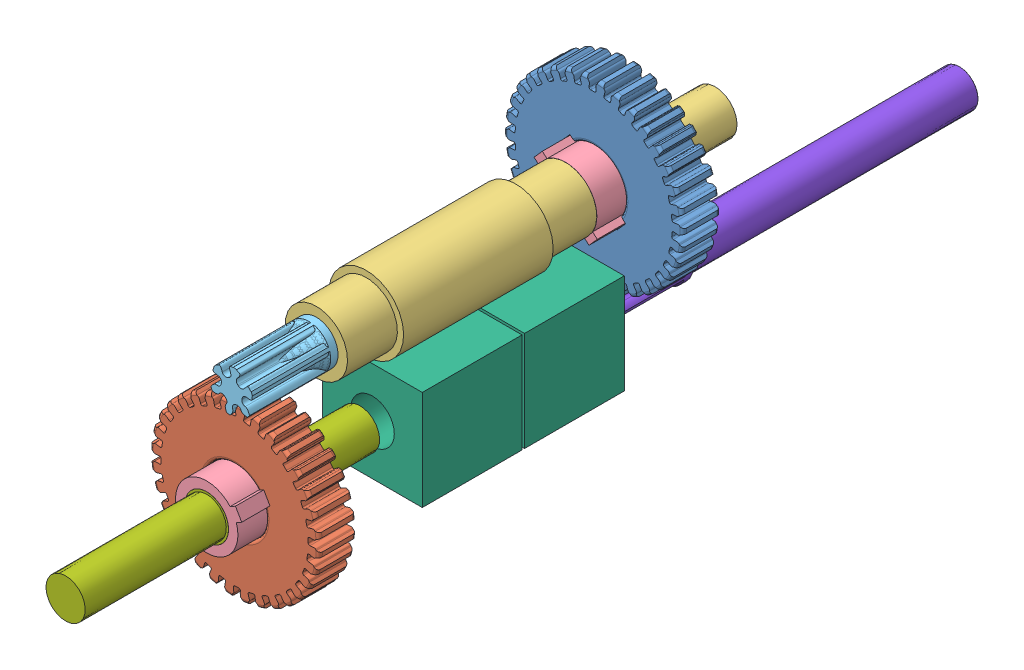
SolidWorks assembly Gear, configuration Default. Lengths in mm.
Overall size (64.62 86.42 227.72).
12 component instances, 10 part files, 29 mates.
Components (placement in the parent):
- drill-1: drill [Default] at (-20.9902 -5.8686 -75.9138) size (76.2 76.2 76.2) (hidden)
- 34 Tooth Gear-1: 34 Tooth Gear [Default] at (-20.9902 46.4985 -21.6848) x (0 0 -1) z (-0.664493 -0.747295 0) size (9.5 45.81 45.73)
- 32 Tooth Gear-1: 32 Tooth Gear [Default] at (-20.9902 21.924 60.3572) x (0 0 1) z (0.497661 -0.867372 0) size (9.51 43.27 43.27)
- shaft-1: shaft [Default] at (-20.9902 46.4985 -9.8738) x (0.670826 0.741614 0) z (0 0 1) size (19.05 19.05 101.6)
- Bushing GAB20A-1: Bushing GAB20A [Default] at (-20.9902 46.4985 -28.9238) x (0 0 1) z (0.664493 0.747295 0) size (19.05 18.72 15.88)
- Bushing GAB20A-2: Bushing GAB20A [Default] at (-20.9902 21.924 62.5162) x (0 0 1) z (-0.497661 0.867372 0) size (19.05 18.72 15.88)
- 6 Tooth Pinion 1-2: 6 Tooth Pinion 1 [Default] at (-20.9902 46.4985 74.2002) x (0 0 -1) z (-0.987719 0.15624 0) size (59.69 11.6 11.05)
- otherside-1: otherside [Default] at (-20.9902 9.224 0.5962) x (-1 0 0) z (0 0 -1) size (25.4 25.4 25.4)
- Shaft2-1: Shaft2 [Default] at (-20.9902 21.924 42.5162) x (-0.998091 -0.061753 0) z (0 0 1) size (11.13 11.13 75)
- case-1: case [Default] at (-20.9902 32.2314 -37.8138) x (-1 0 0) z (0 0 -1) size (50.8 76.2 127) (hidden)
- 6 Tooth Pinion 2-1: 6 Tooth Pinion 2 [Default] at (-20.9902 20.654 -16.2746) x (0 0 -1) z (-0.304987 -0.952356 0) size (94.95 11.6 11.05)
- otherside-2: otherside [Default] at (-20.9902 9.224 26.645) x (-1 0 0) z (0 0 -1) size (25.4 25.4 25.4)
Mates (geometry in assembly coordinates):
- Concentric3: concentric anti-aligned: cylinder of shaft-1 through (-20.9902 46.4985 -47.9738) axis (0 0 1) radius 5.5626; cylinder of Bushing GAB20A-1 through (-20.9902 46.4985 5.8596) axis (0 0 -1) radius 5.5626
- Concentric4: concentric anti-aligned: circle of 34 Tooth Gear-1; circle of Bushing GAB20A-1
- Parallel2: parallel anti-aligned: line of 34 Tooth Gear-1 through (-14.964 38.9987 -16.9858) axis (0.664493 0.747295 0); line of Bushing GAB20A-1 through (-12.9407 41.4652 -9.8738) axis (-0.664493 -0.747295 0)
- Concentric5: concentric anti-aligned: circle of drill-1; circle of shaft-1
- Distance4: distance = 2.54 mm aligned: plane of Bushing GAB20A-1 through (-20.9902 46.4985 -28.9238) normal (0 0 -1); plane of 34 Tooth Gear-1 through (-4.1765 35.2417 -26.3838) normal (0 0 -1)
- Parallel3: parallel aligned: plane of drill-1 through (-59.0902 70.3314 -37.8138) normal (-1 0 0); plane of otherside-1 through (-33.6902 34.624 -12.1038) normal (-1 0 0)
- Concentric6: concentric anti-aligned: circle of otherside-1; circle of Shaft2-1
- Concentric7: concentric anti-aligned: circle of Bushing GAB20A-2; circle of Shaft2-1
- Concentric8: concentric anti-aligned: circle of 32 Tooth Gear-1; circle of Bushing GAB20A-2
- Distance6: distance = 8.89 mm anti-aligned: plane of shaft-1 through (-20.9902 46.4985 53.6262) normal (0 0 1); plane of Bushing GAB20A-2 through (-20.9902 21.924 62.5162) normal (0 0 -1)
- Distance7: distance = 2.54 mm aligned: plane of 32 Tooth Gear-1 through (-35.889 10.1878 65.0562) normal (0 0 -1); plane of Bushing GAB20A-2 through (-20.9902 21.924 62.5162) normal (0 0 -1)
- Parallel4: parallel anti-aligned: line of 32 Tooth Gear-1 through (-11.9652 25.2573 65.0562) axis (-0.497661 0.867372 0); line of Bushing GAB20A-2 through (-13.6617 27.959 62.5162) axis (0.497661 -0.867372 0)
- GearMate2: gear = 152.4 : 812.8 mm: circle of 32 Tooth Gear-1; circle of 6 Tooth Pinion 1-2
- Concentric14: concentric aligned: circle of drill-1; circle of otherside-1
- Distance8: distance = 27.94 mm anti-aligned: plane of drill-1 through (-59.0902 70.3314 -37.8138) normal (0 0 1); plane of shaft-1 through (-20.9902 46.4985 -9.8738) normal (0 0 -1)
- Coincident20: coincident anti-aligned: plane of drill-1 through (-59.0902 70.3314 -37.8138) normal (0 0 1); plane of case-1 through (-46.3902 70.3314 -37.8138) normal (0 0 -1)
- Parallel6: parallel aligned: line of drill-1 through (17.1098 70.3314 -114.0138) axis (-1 0 0); line of case-1 through (4.4098 70.3314 -37.8138) axis (-1 0 0)
- Coincident21: coincident anti-aligned: line of drill-1 through (-59.0902 70.3314 -37.8138) axis (1 0 0); line of case-1 through (4.4098 70.3314 -37.8138) axis (-1 0 0)
- Concentric18: concentric aligned: circle of otherside-1; circle of case-1
- Distance9: distance = 0 mm anti-aligned: plane of Bushing GAB20A-1 through (-20.9902 46.4985 -9.8738) normal (0 0 1); plane of shaft-1 through (-20.9902 46.4985 -9.8738) normal (0 0 -1)
- Concentric21: concentric aligned: circle of drill-1; circle of 6 Tooth Pinion 2-1
- Coincident27: coincident anti-aligned: plane of drill-1 through (-20.9902 20.654 -110.2038) normal (0 0 1); plane of 6 Tooth Pinion 2-1 through (-20.9902 20.654 -110.2038) normal (0 0 -1)
- GearMate5: gear = 152.4 : 863.6 mm: circle of 34 Tooth Gear-1; circle of 6 Tooth Pinion 2-1
- Coincident28: coincident anti-aligned: plane of shaft-1 through (-20.9902 46.4985 53.6262) normal (0 0 1); plane of 6 Tooth Pinion 1-2 through (-20.9902 46.4985 53.6262) normal (0 0 -1)
- Concentric23: concentric anti-aligned: circle of shaft-1; circle of 6 Tooth Pinion 1-2
- Parallel7: parallel aligned: plane of otherside-1 through (-8.2902 34.624 -12.1038) normal (1 0 0); plane of otherside-2 through (-8.2902 34.624 13.945) normal (1 0 0)
- Parallel8: parallel aligned: plane of otherside-1 through (-20.9902 34.624 0.5962) normal (0 1 0); plane of otherside-2 through (-20.9902 34.624 26.645) normal (0 1 0)
- Coincident29: coincident aligned: line of otherside-1 through (-8.2902 34.624 -12.1038) axis (0 0 1); line of otherside-2 through (-8.2902 34.624 13.945) axis (0 0 1)
- Coincident31: coincident anti-aligned: plane of Bushing GAB20A-2 through (-20.9902 21.924 62.5162) normal (0 0 -1); circle of Shaft2-1
